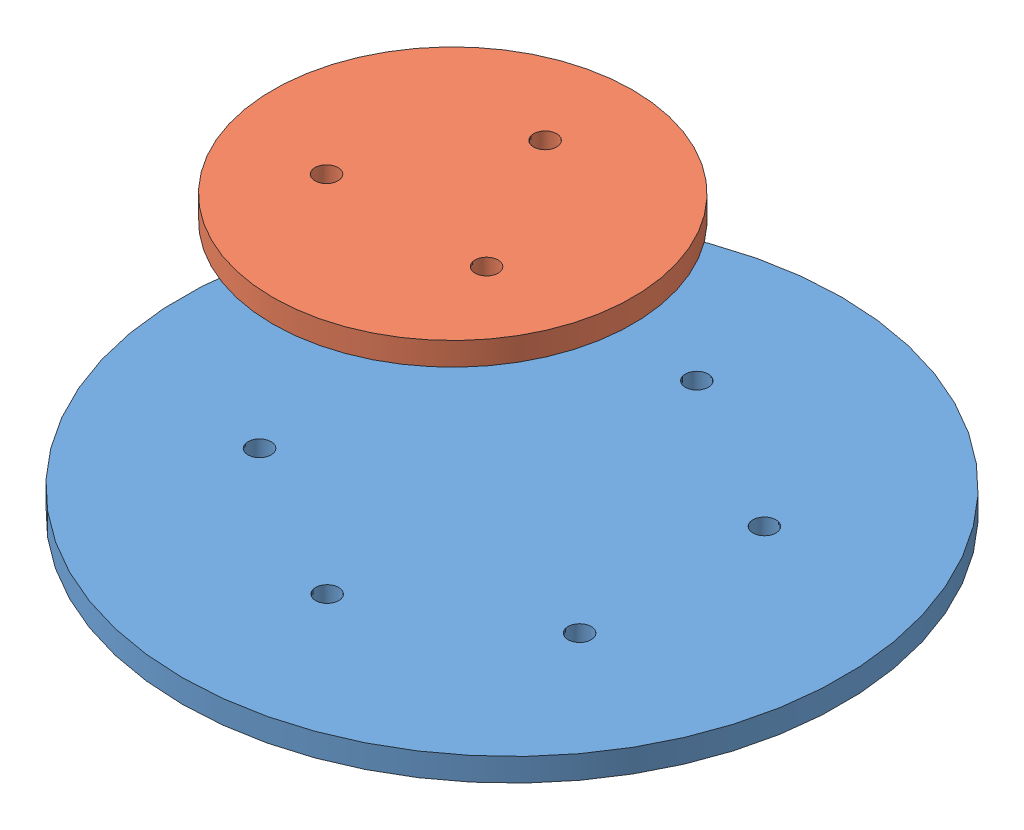
SolidWorks assembly sim_model, configuration 默认. Lengths in mm.
Overall size (285.42 107.27 285.42).
2 component instances, 2 part files, 0 mates.
Components (placement in the parent):
- downPart-1: downPart [默认] at (-22.3694 21.0976 285.422) size (285.42 10 285.42)
- upPart-1: upPart [默认] at (-48.0196 118.3691 285.422) size (155.71 10 155.71)
